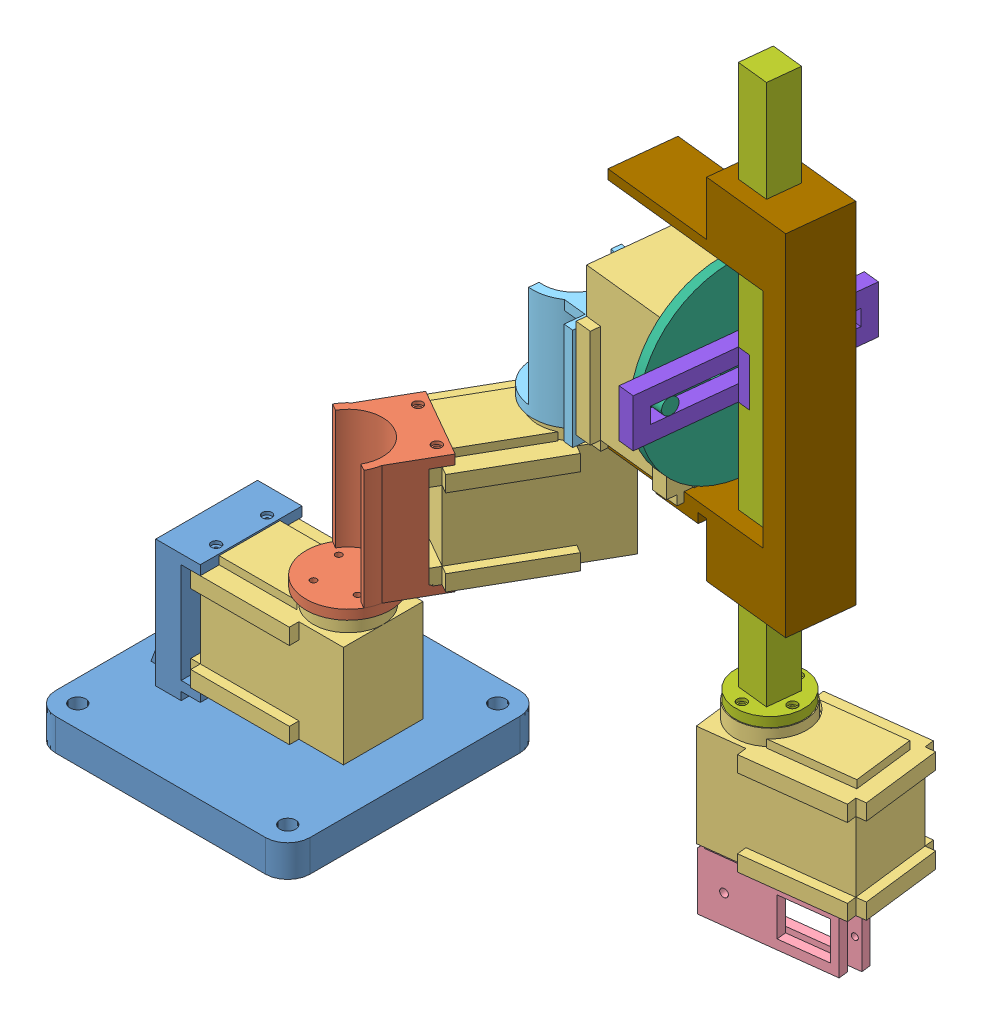
SolidWorks assembly FinalAssembly, configuration Default. Lengths in mm.
Overall size (192.69 238 113.36).
12 component instances, 9 part files, 31 mates.
Components (placement in the parent):
- base-1: base [Default] at (22.1491 26.3195 65.0963) size (80 50 80)
- rotor-1: rotor [Default] at (41.6491 78.3195 65.5963) x (0.497117 0 -0.867683) z (0.867683 0 0.497117) size (34.5 40.5 26.5)
- servomotor-1: servomotor [Default] at (30.1491 41.3195 65.5963) x (-1 0 0) z (0 0 -1) size (48 37 31)
- servomotor-2: servomotor [Default] at (61.9067 83.8195 30.2382) x (-0.497117 0 0.867683) z (-0.867683 0 -0.497117) size (48 37 31)
- servomotor-3: servomotor [Default] at (147.6464 38.6199 26.2073) x (0.992595 0 -0.12147) z (0.12147 0 0.992595) size (48 37 31)
- endeffector-1: endeffector [Default] at (137.5382 38.6199 25.9331) x (0.992595 0 -0.12147) z (-0.12147 0 -0.992595) size (42.5 28 22)
- servomotor-4: servomotor [Default] at (86.5676 149.3195 21.8001) x (0 -1 0) z (-0.107235 0 0.994234) size (48 37 31)
- Link3-1: Link3 [Default] at (83.5313 139.8195 21.9756) x (0.107235 0 -0.994234) z (0.994234 0 0.107235) size (32 35 32.25)
- rotor 2-1: rotor 2 [Default] at (126.3369 160.8195 26.0895) x (-0.012012 -0.993707 0.111368) z (-0.994234 0 -0.107235) size (60 60 8)
- slidingBarPrismaticLink-1: slidingBarPrismaticLink [Default] at (136.2316 163.6199 27.6042) x (-0.107235 0 0.994234) z (-0.994234 0 -0.107235) size (21.5 173 21.5)
- board-1: board [Default] at (126.2892 163.6199 26.5318) x (-0.107235 0 0.994234) z (0 1 0) size (70 9 15)
- PrismaticLinkOuter-1: PrismaticLinkOuter [Default] at (136.2316 161.8195 27.6042) x (0.994234 0 0.107235) z (0 -1 0) size (63 20 110)
Mates (geometry in assembly coordinates):
- Coincident1: coincident anti-aligned: plane of base-1 through (4.6491 76.3195 81.0963) normal (1 0 0); plane of servomotor-1 through (4.6491 41.3195 65.5963) normal (-1 0 0)
- Coincident2: coincident anti-aligned: plane of base-1 through (10.6491 73.3195 81.0963) normal (0 -1 0); plane of servomotor-1 through (30.1491 73.3195 65.5963) normal (0 1 0)
- Coincident4: coincident aligned: plane of base-1 through (-3.3509 76.3195 81.0963) normal (0 0 1); plane of servomotor-1 through (30.1491 41.3195 81.0963) normal (0 0 1)
- Coincident5: coincident anti-aligned: plane of rotor-1 through (41.6491 78.3195 65.5963) normal (0 -1 0); plane of servomotor-1 through (41.6491 78.3195 65.5963) normal (0 1 0)
- Concentric1: concentric aligned: circle of rotor-1; circle of servomotor-1
- Coincident6: coincident anti-aligned: plane of rotor-1 through (49.2302 78.3195 52.3641) normal (0.497117 0 -0.867683); plane of servomotor-2 through (49.2302 83.8195 52.3641) normal (-0.497117 0 0.867683)
- Coincident7: coincident anti-aligned: plane of rotor-1 through (63.0589 115.8195 53.3719) normal (0 -1 0); plane of servomotor-2 through (61.9067 115.8195 30.2382) normal (0 1 0)
- Coincident8: coincident aligned: plane of rotor-1 through (30.8021 78.3195 59.384) normal (-0.867683 0 -0.497117); plane of servomotor-2 through (62.2458 115.8195 4.5013) normal (-0.867683 0 -0.497117)
- Coincident9: coincident anti-aligned: plane of servomotor-3 through (147.6464 38.6199 26.2073) normal (0 -1 0); plane of endeffector-1 through (137.5382 38.6199 25.9331) normal (0 1 0)
- Coincident10: coincident aligned: plane of servomotor-3 through (126.8314 70.6199 41.3478) normal (-0.992595 0 0.12147); plane of endeffector-1 through (123.7946 35.6199 16.5329) normal (-0.992595 0 0.12147)
- Coincident11: coincident aligned: plane of servomotor-3 through (123.7946 70.6199 16.5329) normal (-0.12147 0 -0.992595); plane of endeffector-1 through (123.7946 35.6199 16.5329) normal (-0.12147 0 -0.992595)
- Coincident15: coincident aligned: plane of servomotor-4 through (86.5676 123.8195 21.8001) normal (0 -1 0); plane of Link3-1 through (84.7982 123.8195 38.205) normal (0 -1 0)
- Coincident17: coincident anti-aligned: plane of servomotor-4 through (86.5676 149.3195 21.8001) normal (-0.994234 0 -0.107235); plane of Link3-1 through (86.514 139.8195 22.2973) normal (0.994234 0 0.107235)
- Coincident18: coincident aligned: plane of servomotor-4 through (88.2297 149.3195 6.3895) normal (0.107235 0 -0.994234); plane of Link3-1 through (88.2297 123.8195 6.3895) normal (0.107235 0 -0.994234)
- Coincident19: coincident aligned: plane of servomotor-4 through (86.5676 123.8195 21.8001) normal (0 -1 0); plane of Link3-1 through (84.7982 123.8195 38.205) normal (0 -1 0)
- Coincident20: coincident anti-aligned: plane of servomotor-2 through (67.6235 120.8195 20.2598) normal (0 1 0); plane of Link3-1 through (67.6235 120.8195 20.2598) normal (0 -1 0)
- Concentric2: concentric anti-aligned: circle of servomotor-2; circle of Link3-1
- Coincident22: coincident anti-aligned: plane of servomotor-4 through (123.3542 160.8195 25.7678) normal (0.994234 0 0.107235); plane of rotor 2-1 through (123.3542 160.8195 25.7678) normal (-0.994234 0 -0.107235)
- Concentric3: concentric anti-aligned: circle of servomotor-4; circle of rotor 2-1
- Coincident23: coincident anti-aligned: plane of servomotor-3 through (136.2316 75.6199 27.6042) normal (0 1 0); plane of slidingBarPrismaticLink-1 through (136.2316 75.6199 27.6042) normal (0 -1 0)
- Concentric4: concentric anti-aligned: circle of servomotor-3; circle of slidingBarPrismaticLink-1
- Coincident24: coincident anti-aligned: plane of slidingBarPrismaticLink-1 through (135.2373 163.6199 27.497) normal (-0.994234 0 -0.107235); plane of board-1 through (135.2373 163.6199 27.497) normal (0.994234 0 0.107235)
- Coincident25: coincident anti-aligned: plane of slidingBarPrismaticLink-1 through (135.7735 171.1199 22.5258) normal (0 -1 0); plane of board-1 through (135.0136 171.1199 -7.7302) normal (0 1 0)
- Coincident26: coincident aligned: plane of slidingBarPrismaticLink-1 through (130.7242 248.6199 32.0392) normal (-0.107235 0 0.994234); plane of board-1 through (134.7011 171.1199 32.4681) normal (-0.107235 0 0.994234)
- Coincident29: coincident anti-aligned: plane of rotor 2-1 through (126.3369 160.8195 26.0895) normal (0.994234 0 0.107235); plane of board-1 through (126.2892 163.6199 26.5318) normal (-0.994234 0 -0.107235)
- Tangent2: tangent anti-aligned: cylinder of rotor 2-1 through (128.6441 163.6199 51.3251) axis (-0.994234 0 -0.107235) radius 2.5; plane of board-1 through (128.0433 161.1199 56.895) normal (0 1 0)
- Coincident35: coincident anti-aligned: plane of slidingBarPrismaticLink-1 through (141.7389 248.6199 23.1692) normal (0.994234 0 0.107235); plane of PrismaticLinkOuter-1 through (141.7389 216.8195 23.1692) normal (-0.994234 0 -0.107235)
- Coincident36: coincident anti-aligned: plane of servomotor-4 through (117.0426 126.8195 37.6596) normal (0 -1 0); plane of PrismaticLinkOuter-1 through (135.1592 126.8195 37.5465) normal (0 1 0)
- Parallel2: parallel anti-aligned: plane of servomotor-4 through (86.5676 123.8195 21.8001) normal (0 -1 0); plane of PrismaticLinkOuter-1 through (135.1592 123.8195 37.5465) normal (0 1 0)
- Coincident38: coincident anti-aligned: plane of slidingBarPrismaticLink-1 through (131.7966 248.6199 22.0969) normal (0.107235 0 -0.994234); plane of PrismaticLinkOuter-1 through (141.7389 216.8195 23.1692) normal (-0.107235 0 0.994234)
- Coincident39: coincident aligned: plane of servomotor-4 through (121.8933 154.2723 15.9997) normal (0.107235 0 -0.994234); plane of PrismaticLinkOuter-1 through (137.3039 161.8195 17.6619) normal (0.107235 0 -0.994234)
